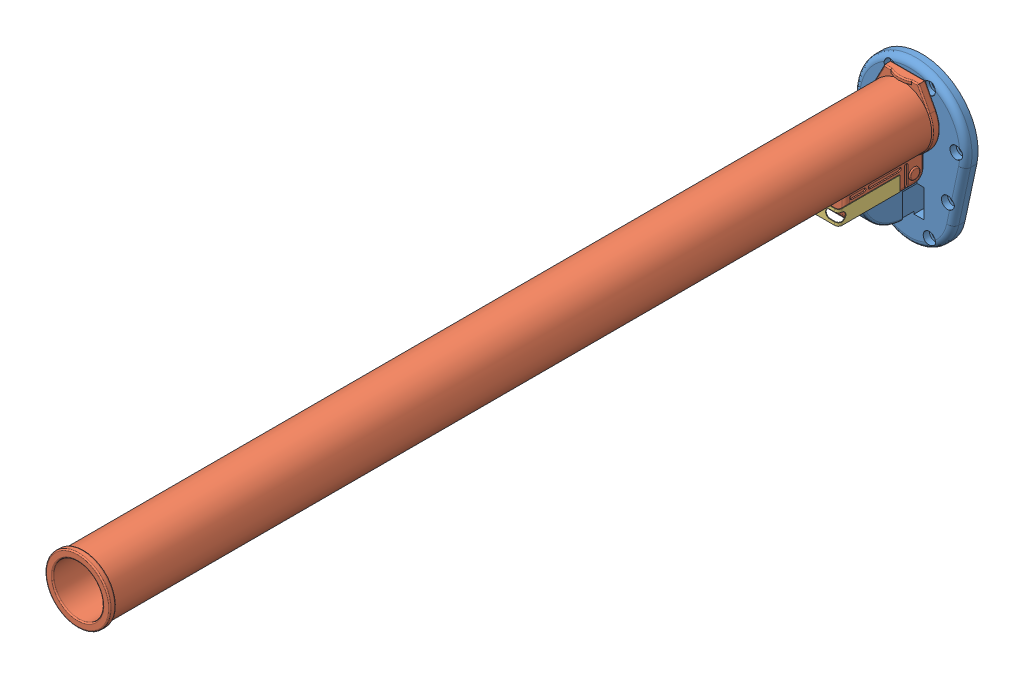
SolidWorks assembly pied de table rabattable Camar, configuration 1. Lengths in mm.
Overall size (92 130 692).
3 component instances, 3 part files, 8 mates.
Components (placement in the parent):
- base pied-1: base pied [1] at origin size (92 130 55)
- tube pied-1: tube pied [1] at (0 11 351.5) x (1 0 0) z (0 1 0) size (53 681 70.75)
- bouton pied-1: bouton pied [1] at (0 -23.0208 82) x (-1 0 0) z (0 0 -1) size (28.01 12 50.5)
Mates (geometry in assembly coordinates):
- Coaxiale1: concentric: cylinder of base pied-1 through (-22.5 -22 20) axis (1 0 0) radius 2.5; circle of tube pied-1
- Coïncidente1: coincident: plane of tube pied-1 through (0 11 351.5) normal (1 0 0); plane of assembly through (0 0 0) normal (1 0 0)
- Coïncidente3: coincident: plane of bouton pied-1 through (0 -23.0208 82) normal (-1 0 0); plane of assembly through (0 0 0) normal (1 0 0)
- Coïncidente4: coincident: plane of tube pied-1; plane of bouton pied-1
- Coïncidente5: coincident: plane of tube pied-1; plane of bouton pied-1
- Parallèle1: parallel: plane of tube pied-1; plane of assembly through (0 0 0) normal (0 0 1)
- Parallèle2: parallel: plane of tube pied-1; plane of assembly through (0 0 0) normal (0 1 0)
- LimitAngle1: limit planar angle = 0 rad: plane of tube pied-1 through (-25.75 11 11) normal (0 0 -1); plane of base pied-1 through (0 0 10) normal (0 0 1)
